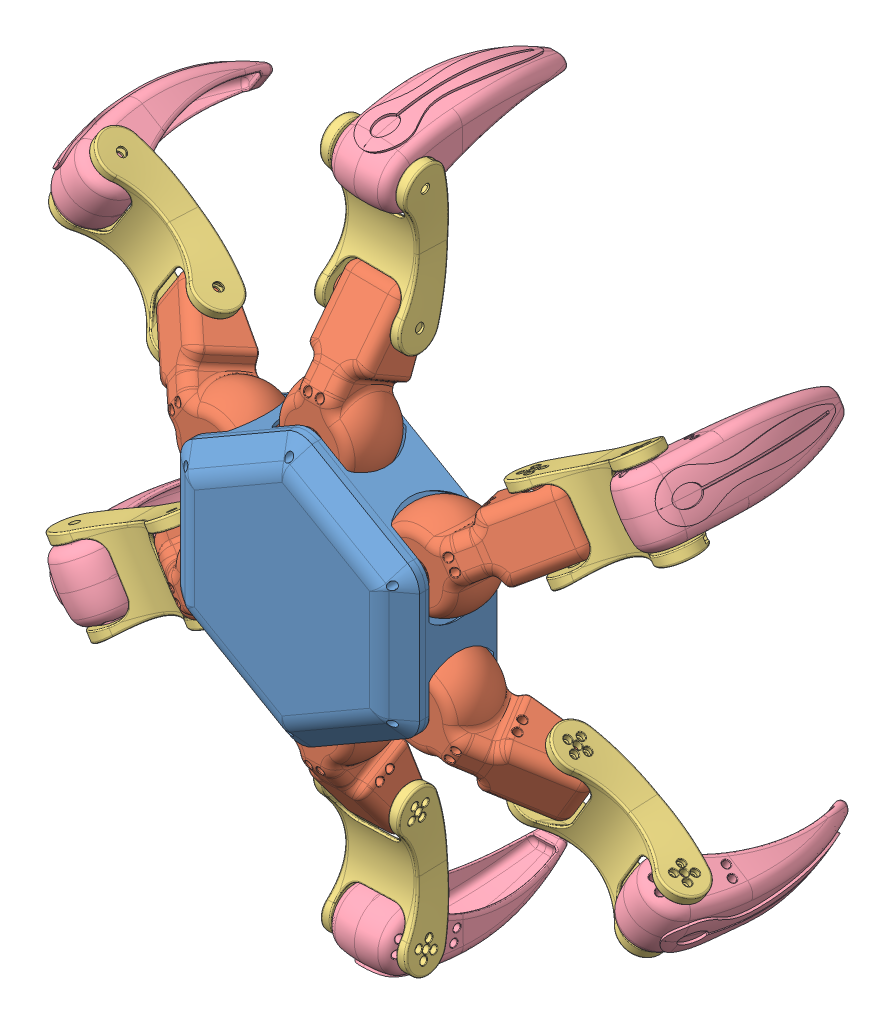
SolidWorks assembly Spider_Assembly, configuration Default. Lengths in mm.
Overall size (643.84 710.96 257.37).
19 component instances, 4 part files, 36 mates.
Components (placement in the parent):
- Spider_Body_Assemnly-1: Spider_Body_Assemnly [Default] at (0 0 -77) x (-1 0 0) z (0 1 0) size (200 80.01 224.75)
- Spider_Coxa_Assemnly-1: Spider_Coxa_Assemnly [Default] at (-13.7144 83.0658 -74.7787) x (-0.999921 0.012544 0) z (0.012544 0.999921 0) size (74 75.15 121.21)
- Spider_Fimur_Assemnly-1: Spider_Fimur_Assemnly [Default] at (-25.2179 182.5046 -28.2976) x (-0.012537 -0.999331 0.034349) z (-0.999921 0.012544 0) size (136 45.7 76.66)
- Spider_Tibia_Assemnly-1: Spider_Tibia_Assemnly [Default] at (-13.5847 93.4004 -43.4782) x (-0.999921 0.012544 0) z (0.011354 0.905068 -0.425115) size (68.7 154.29 100.09)
- Spider_Coxa_Assemnly-2: Spider_Coxa_Assemnly [Default] at (-79.4845 29.4053 -74.7787) x (-0.539492 -0.841991 0) z (-0.841991 0.539492 0) size (74 75.15 121.21)
- Spider_Tibia_Assemnly-2: Spider_Tibia_Assemnly [Default] at (-88.1868 34.9812 -43.4782) x (-0.539492 -0.841991 0) z (-0.762119 0.488316 -0.425115) size (68.7 154.29 100.09)
- Spider_Fimur_Assemnly-2: Spider_Fimur_Assemnly [Default] at (-169.9615 72.2343 -28.2976) x (0.841494 -0.539174 0.034349) z (-0.539492 -0.841991 0) size (136 45.7 76.66)
- Spider_Coxa_Assemnly-3: Spider_Coxa_Assemnly [Default] at (-64.9426 -52.3727 -74.7787) x (0.530374 -0.847764 0) z (-0.847764 -0.530374 0) size (74 75.15 121.21)
- Spider_Fimur_Assemnly-3: Spider_Fimur_Assemnly [Default] at (-142.352 -115.8407 -28.2976) x (0.847264 0.530061 0.034349) z (0.530374 -0.847764 0) size (136 45.7 76.66)
- Spider_Tibia_Assemnly-3: Spider_Tibia_Assemnly [Default] at (-73.7046 -57.8543 -43.4782) x (0.530374 -0.847764 0) z (-0.767344 -0.480062 -0.425115) size (68.7 154.29 100.09)
- Spider_Coxa_Assemnly-4: Spider_Coxa_Assemnly [Default] at (12.9534 -82.4783 -74.7787) x (0.999504 0.0315 0) z (0.0315 -0.999504 0) size (74 75.15 121.21)
- Spider_Fimur_Assemnly-4: Spider_Fimur_Assemnly [Default] at (28.8246 -181.3141 -28.2976) x (-0.031481 0.998914 0.034349) z (0.999504 0.0315 0) size (136 45.7 76.66)
- Spider_Tibia_Assemnly-4: Spider_Tibia_Assemnly [Default] at (13.2789 -92.8086 -43.4782) x (0.999504 0.0315 0) z (0.028512 -0.90469 -0.425115) size (68.7 154.29 100.09)
- Spider_Coxa_Assemnly-5: Spider_Coxa_Assemnly [Default] at (78.8299 -29.6426 -74.7787) x (0.512391 0.858752 0) z (0.858752 -0.512391 0) size (74 75.15 121.21)
- Spider_Fimur_Assemnly-5: Spider_Fimur_Assemnly [Default] at (170.6256 -69.5671 -28.2976) x (-0.858246 0.512088 0.034349) z (0.512391 0.858752 0) size (136 45.7 76.66)
- Spider_Tibia_Assemnly-5: Spider_Tibia_Assemnly [Default] at (87.7055 -34.9384 -43.4782) x (0.512391 0.858752 0) z (0.777291 -0.463785 -0.425115) size (68.7 154.29 100.09)
- Spider_Coxa_Assemnly-6: Spider_Coxa_Assemnly [Default] at (64.8783 51.7103 -74.7787) x (-0.556006 0.831179 0) z (0.831179 0.556006 0) size (74 75.15 121.21)
- Spider_Fimur_Assemnly-6: Spider_Fimur_Assemnly [Default] at (140.3142 117.5118 -28.2976) x (-0.830688 -0.555678 0.034349) z (-0.556006 0.831179 0) size (136 45.7 76.66)
- Spider_Tibia_Assemnly-6: Spider_Tibia_Assemnly [Default] at (73.4689 57.4569 -43.4782) x (-0.556006 0.831179 0) z (0.752332 0.503263 -0.425115) size (68.7 154.29 100.09)
Mates (geometry in assembly coordinates):
- Coincident1: coincident anti-aligned: plane of Spider_Body_Assemnly-1 through (0 0 -22.9) normal (0 0 -1); plane of Spider_Coxa_Assemnly-1 through (0 100 -22.9) normal (0 0 1)
- Coincident2: coincident anti-aligned: plane of Spider_Coxa_Assemnly-1 through (-25.2914 176.6469 -78.1258) normal (-0.999921 0.012544 0); plane of Spider_Fimur_Assemnly-1 through (-24.639 228.6472 -20.6646) normal (0.999921 -0.012544 0)
- Coincident3: coincident anti-aligned: plane of Spider_Fimur_Assemnly-1 through (-24.639 228.6472 -20.6646) normal (0.999921 -0.012544 0); plane of Spider_Tibia_Assemnly-1 through (-24.0377 276.58 -81.5608) normal (-0.999921 0.012544 0)
- Concentric1: concentric anti-aligned: cylinder of Spider_Body_Assemnly-1 through (0 100 0.005) axis (0 0 -1) radius 1.5; cylinder of Spider_Coxa_Assemnly-1 through (0 100 -24.9) axis (0 0 1) radius 1.5
- Concentric2: concentric anti-aligned: cylinder of Spider_Coxa_Assemnly-1 through (-23.2915 176.6218 -78.1258) axis (-0.999921 0.012544 0) radius 1.5; cylinder of Spider_Fimur_Assemnly-1 through (-36.1197 176.7827 -78.1258) axis (0.999921 -0.012544 0) radius 3
- Concentric3: concentric anti-aligned: cylinder of Spider_Fimur_Assemnly-1 through (-34.866 276.7158 -81.5608) axis (0.999921 -0.012544 0) radius 3; cylinder of Spider_Tibia_Assemnly-1 through (-22.0378 276.5549 -81.5608) axis (-0.999921 0.012544 0) radius 1.5
- Concentric4: concentric anti-aligned: cylinder of Spider_Coxa_Assemnly-2 through (-163.9499 70.7578 -78.1258) axis (-0.539492 -0.841991 0) radius 1.5; cylinder of Spider_Fimur_Assemnly-2 through (-170.8711 59.9558 -78.1258) axis (0.539492 0.841991 0) radius 3
- Concentric5: concentric anti-aligned: cylinder of Spider_Tibia_Assemnly-2 through (-248.0993 124.6752 -81.5608) axis (-0.539492 -0.841991 0) radius 1.5; cylinder of Spider_Fimur_Assemnly-2 through (-255.0205 113.8732 -81.5608) axis (0.539492 0.841991 0) radius 3
- Coincident4: coincident anti-aligned: plane of Spider_Tibia_Assemnly-2 through (-249.1783 122.9912 -81.5608) normal (-0.539492 -0.841991 0); plane of Spider_Fimur_Assemnly-2 through (-208.8162 97.1299 -20.6646) normal (0.539492 0.841991 0)
- Coincident5: coincident anti-aligned: plane of Spider_Coxa_Assemnly-2 through (-165.0289 69.0739 -78.1258) normal (-0.539492 -0.841991 0); plane of Spider_Fimur_Assemnly-2 through (-208.8162 97.1299 -20.6646) normal (0.539492 0.841991 0)
- Coincident6: coincident anti-aligned: plane of Spider_Body_Assemnly-1 through (0 0 -22.9) normal (0 0 -1); plane of Spider_Coxa_Assemnly-2 through (-86.603 50.0009 -22.9) normal (0 0 1)
- Concentric6: concentric anti-aligned: cylinder of Spider_Body_Assemnly-1 through (-86.603 50.0009 0.005) axis (0 0 -1) radius 1.5; cylinder of Spider_Coxa_Assemnly-2 through (-86.603 50.0009 -24.9) axis (0 0 1) radius 1.5
- Concentric7: concentric anti-aligned: cylinder of Spider_Coxa_Assemnly-3 through (-138.4464 -111.0382 -78.1258) axis (0.530374 -0.847764 0) radius 1.5; cylinder of Spider_Fimur_Assemnly-3 through (-131.6421 -121.9143 -78.1258) axis (-0.530374 0.847764 0) radius 3
- Concentric8: concentric anti-aligned: cylinder of Spider_Fimur_Assemnly-3 through (-216.3685 -174.9203 -81.5608) axis (-0.530374 0.847764 0) radius 3; cylinder of Spider_Tibia_Assemnly-3 through (-223.1727 -164.0443 -81.5608) axis (0.530374 -0.847764 0) radius 1.5
- Coincident7: coincident anti-aligned: plane of Spider_Fimur_Assemnly-3 through (-181.4731 -140.3155 -20.6646) normal (-0.530374 0.847764 0); plane of Spider_Tibia_Assemnly-3 through (-222.112 -165.7398 -81.5608) normal (0.530374 -0.847764 0)
- Coincident8: coincident anti-aligned: plane of Spider_Coxa_Assemnly-3 through (-137.3856 -112.7337 -78.1258) normal (0.530374 -0.847764 0); plane of Spider_Fimur_Assemnly-3 through (-181.4731 -140.3155 -20.6646) normal (-0.530374 0.847764 0)
- Coincident9: coincident anti-aligned: plane of Spider_Body_Assemnly-1 through (0 0 -22.9) normal (0 0 -1); plane of Spider_Coxa_Assemnly-3 through (-86.604 -49.9991 -22.9) normal (0 0 1)
- Concentric9: concentric anti-aligned: cylinder of Spider_Body_Assemnly-1 through (-86.604 -49.9991 0.005) axis (0 0 -1) radius 1.5; cylinder of Spider_Coxa_Assemnly-3 through (-86.604 -49.9991 -24.9) axis (0 0 1) radius 1.5
- Coincident10: coincident anti-aligned: plane of Spider_Fimur_Assemnly-4 through (30.2782 -227.4374 -20.6646) normal (-0.999504 -0.0315 0); plane of Spider_Tibia_Assemnly-4 through (31.7882 -275.3502 -81.5608) normal (0.999504 0.0315 0)
- Coincident11: coincident anti-aligned: plane of Spider_Coxa_Assemnly-4 through (28.64 -175.4588 -78.1258) normal (0.999504 0.0315 0); plane of Spider_Fimur_Assemnly-4 through (30.2782 -227.4374 -20.6646) normal (-0.999504 -0.0315 0)
- Concentric10: concentric anti-aligned: cylinder of Spider_Coxa_Assemnly-4 through (26.641 -175.5218 -78.1258) axis (0.999504 0.0315 0) radius 1.5; cylinder of Spider_Fimur_Assemnly-4 through (39.4638 -175.1177 -78.1258) axis (-0.999504 -0.0315 0) radius 3
- Concentric11: concentric anti-aligned: cylinder of Spider_Fimur_Assemnly-4 through (42.6119 -275.0091 -81.5608) axis (-0.999504 -0.0315 0) radius 3; cylinder of Spider_Tibia_Assemnly-4 through (29.7891 -275.4132 -81.5608) axis (0.999504 0.0315 0) radius 1.5
- Coincident12: coincident anti-aligned: plane of Spider_Body_Assemnly-1 through (0 0 -22.9) normal (0 0 -1); plane of Spider_Coxa_Assemnly-4 through (-0.002 -100 -22.9) normal (0 0 1)
- Concentric12: concentric anti-aligned: cylinder of Spider_Body_Assemnly-1 through (-0.002 -100 0.005) axis (0 0 -1) radius 1.5; cylinder of Spider_Coxa_Assemnly-4 through (-0.002 -100 -24.9) axis (0 0 1) radius 1.5
- Concentric13: concentric anti-aligned: cylinder of Spider_Coxa_Assemnly-5 through (164.57 -68.2829 -78.1258) axis (0.512391 0.858752 0) radius 1.5; cylinder of Spider_Fimur_Assemnly-5 through (171.1435 -57.2658 -78.1258) axis (-0.512391 -0.858752 0) radius 3
- Concentric14: concentric anti-aligned: cylinder of Spider_Fimur_Assemnly-5 through (256.9681 -108.4746 -81.5608) axis (-0.512391 -0.858752 0) radius 3; cylinder of Spider_Tibia_Assemnly-5 through (250.3946 -119.4917 -81.5608) axis (0.512391 0.858752 0) radius 1.5
- Coincident13: coincident anti-aligned: plane of Spider_Fimur_Assemnly-5 through (210.2537 -93.212 -20.6646) normal (-0.512391 -0.858752 0); plane of Spider_Tibia_Assemnly-5 through (251.4194 -117.7742 -81.5608) normal (0.512391 0.858752 0)
- Coincident14: coincident anti-aligned: plane of Spider_Coxa_Assemnly-5 through (165.5948 -66.5654 -78.1258) normal (0.512391 0.858752 0); plane of Spider_Fimur_Assemnly-5 through (210.2537 -93.212 -20.6646) normal (-0.512391 -0.858752 0)
- Coincident15: coincident anti-aligned: plane of Spider_Body_Assemnly-1 through (0 0 -22.9) normal (0 0 -1); plane of Spider_Coxa_Assemnly-5 through (86.601 -50.0009 -22.9) normal (0 0 1)
- Concentric15: concentric anti-aligned: cylinder of Spider_Body_Assemnly-1 through (86.601 -50.0009 0.005) axis (0 0 -1) radius 1.5; cylinder of Spider_Coxa_Assemnly-5 through (86.601 -50.0009 -24.9) axis (0 0 1) radius 1.5
- Coincident16: coincident anti-aligned: plane of Spider_Fimur_Assemnly-6 through (178.6699 143.1694 -20.6646) normal (0.556006 -0.831179 0); plane of Spider_Tibia_Assemnly-6 through (218.5137 169.8224 -81.5608) normal (-0.556006 0.831179 0)
- Coincident17: coincident anti-aligned: plane of Spider_Coxa_Assemnly-6 through (135.4449 114.2546 -78.1258) normal (-0.556006 0.831179 0); plane of Spider_Fimur_Assemnly-6 through (178.6699 143.1694 -20.6646) normal (0.556006 -0.831179 0)
- Concentric16: concentric anti-aligned: cylinder of Spider_Fimur_Assemnly-6 through (212.4927 178.8233 -81.5608) axis (0.556006 -0.831179 0) radius 3; cylinder of Spider_Tibia_Assemnly-6 through (219.6257 168.16 -81.5608) axis (-0.556006 0.831179 0) radius 1.5
- Concentric17: concentric anti-aligned: cylinder of Spider_Coxa_Assemnly-6 through (136.5569 112.5923 -78.1258) axis (-0.556006 0.831179 0) radius 1.5; cylinder of Spider_Fimur_Assemnly-6 through (129.4239 123.2556 -78.1258) axis (0.556006 -0.831179 0) radius 3
- Coincident18: coincident anti-aligned: plane of Spider_Body_Assemnly-1 through (0 0 -22.9) normal (0 0 -1); plane of Spider_Coxa_Assemnly-6 through (86.602 49.9991 -22.9) normal (0 0 1)
- Concentric18: concentric anti-aligned: cylinder of Spider_Body_Assemnly-1 through (86.602 49.9991 0.005) axis (0 0 -1) radius 1.5; cylinder of Spider_Coxa_Assemnly-6 through (86.602 49.9991 -24.9) axis (0 0 1) radius 1.5
